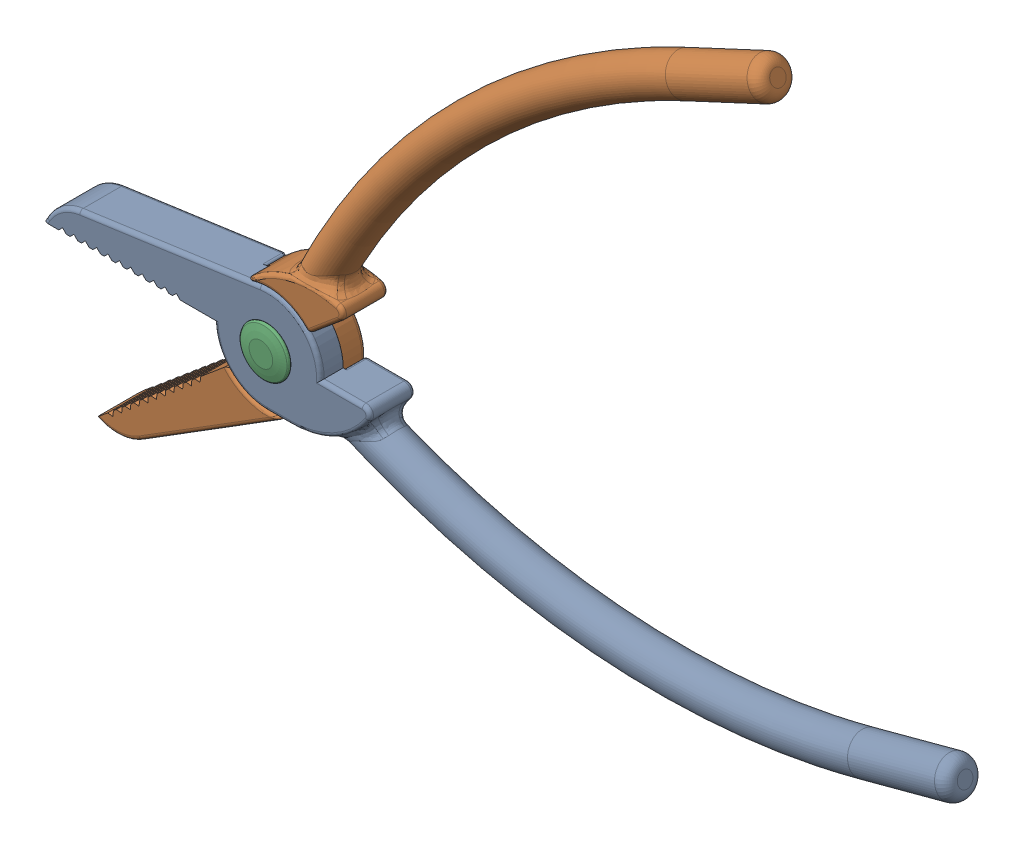
SolidWorks assembly SecJProb1, configuration Default. Lengths in mm.
Overall size (243.58 187.01 15.4).
3 component instances, 3 part files, 6 mates.
Components (placement in the parent):
- Plier-Handle-Base-1: Plier-Handle-Base [Default] at origin size (237.62 44.74 12.21)
- Plier-Handle-1: Plier-Handle [Default] x (0.766044 0.642788 0) z (0 0 -1) size (237.62 44.74 12.21)
- Plier-Joint-1: Plier-Joint [Default] at origin size (13 13 15.4)
Mates (geometry in assembly coordinates):
- Coincident5: coordinate: point of Plier-Handle-Base-1
- Concentric2: concentric aligned: circle of Plier-Handle-Base-1; circle of Plier-Joint-1
- Coincident7: coincident anti-aligned: plane of Plier-Handle-Base-1 through (0 0 6) normal (0 0 1); plane of Plier-Joint-1 through (0 0 6) normal (0 0 -1)
- Concentric3: concentric aligned: circle of Plier-Handle-1; circle of Plier-Joint-1
- Coincident8: coincident anti-aligned: plane of Plier-Handle-1 through (0 0 -6) normal (0 0 -1); plane of Plier-Joint-1 through (0 0 -6) normal (0 0 1)
- Angle1: planar angle = 0.698132 rad anti-aligned: line of Plier-Handle-1 through (18.5083 16.8357 -6) axis (-0.766044 -0.642788 0); line of Plier-Handle-Base-1 through (14.9666 -1 -6) axis (1 0 0)
